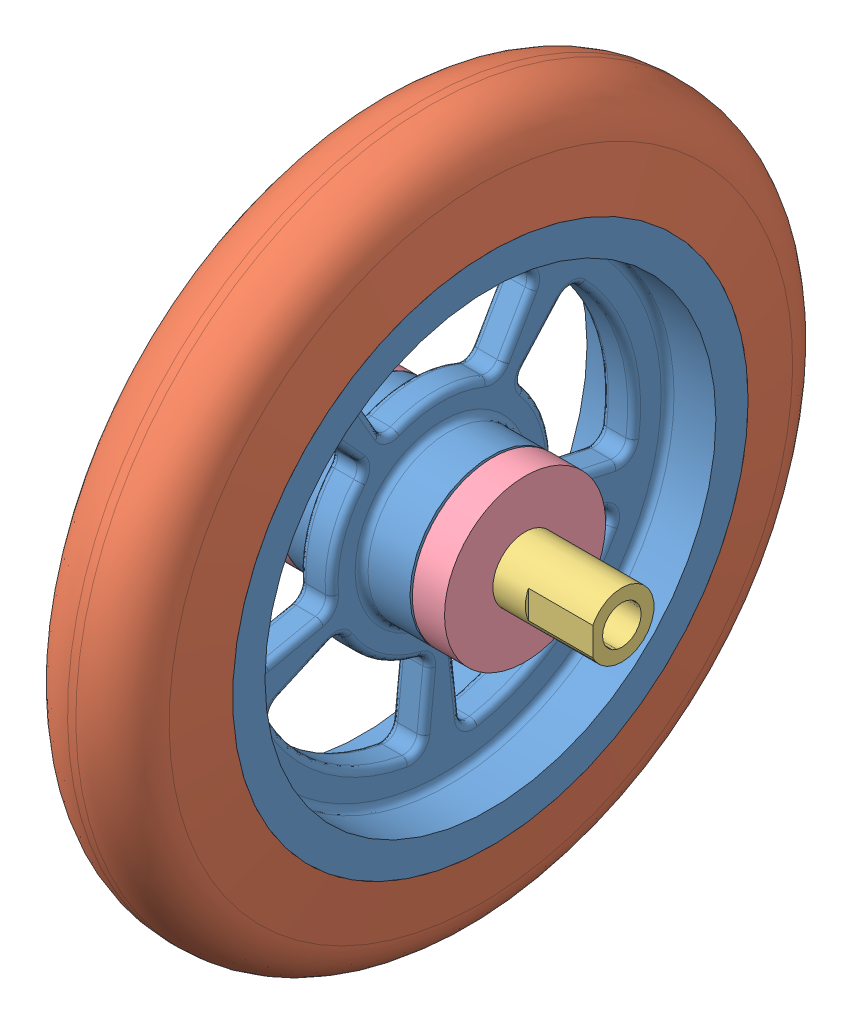
SolidWorks assembly Wheel and Axle, configuration Default. Lengths in mm.
Overall size (60 110 110).
5 component instances, 4 part files, 5 mates.
Components (placement in the parent):
- Wheel-1: Wheel [Default] at (43.5901 43.4624 52.9982) size (20 80 80)
- Tire-1: Tire [Default] at (43.5901 43.4624 52.9982) x (0 0 -1) z (0 1 0) size (110 20 110)
- Axle-2: Axle [Default] at (43.9894 43.4624 52.9982) x (0 1 0) z (-1 0 0) size (10 10 60)
- Washer-2: Washer [Default] at (31.0901 43.4624 52.9982) size (5 25 25)
- Washer-3: Washer [Default] at (56.4676 43.4624 52.9982) size (5 25 25)
Mates (geometry in assembly coordinates):
- Coincident7: coincident anti-aligned: plane of Wheel-1 through (43.5901 43.4624 52.9982) normal (0 0 1); plane of Axle-2 through (43.9894 43.4624 52.9982) normal (0 0 -1)
- Coincident8: coincident aligned: circle of Wheel-1; circle of Tire-1
- Concentric2: concentric anti-aligned: circle of Wheel-1; circle of Washer-3
- Coincident11: coincident anti-aligned: circle of Wheel-1; circle of Washer-2
- Concentric4: concentric aligned: cylinder of Wheel-1 through (88.0288 43.4624 52.9982) axis (1 0 0) radius 5; cylinder of Axle-2 through (13.9894 43.4624 52.9982) axis (1 0 0) radius 5
